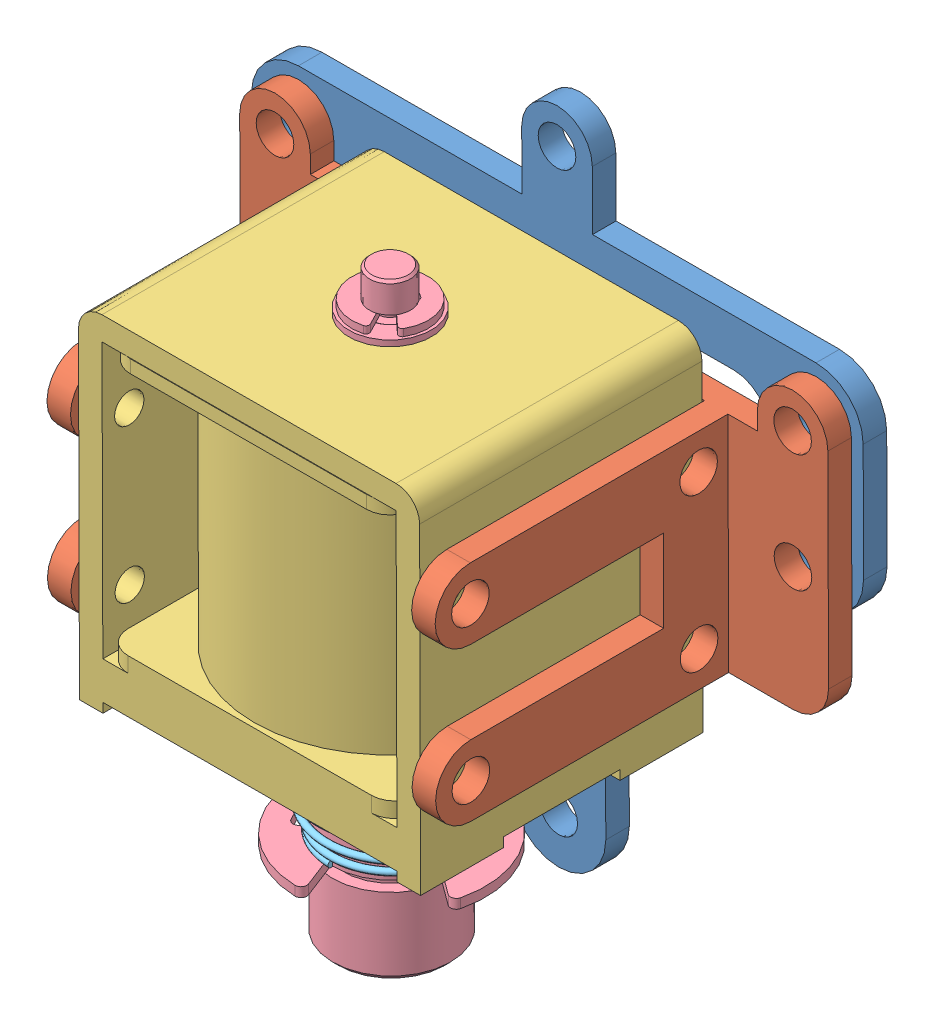
SolidWorks assembly Aimbot-S Swing, configuration Default. Lengths in mm.
Overall size (52.17 56.16 28.9).
6 component instances, 5 part files, 8 mates.
Components (placement in the parent):
- Aimbot Swing-1: Aimbot Swing [Default] at (64.9586 191.5313 171.8045) x (0.999995 0.003011 0) z (0.003011 -0.999995 0) size (52 2 56)
- CB1029 Kicker Stand-2: CB1029 Kicker Stand [Default] at (79.5263 169.075 197.7045) x (0 0 -1) z (0.999995 0.003011 0) size (26.9 23.5 50)
- INPUT kicker-4: INPUT kicker [Default] at (67.8693 174.4365 188.2528) x (-0.999995 -0.003011 0) z (0 0 1) size (29 49.3 24.1)
  - Part5^w_cb1029A-1: Part5^w_cb1029A [Default] at (2.8592 11.2966 11.7516) size (29 29.6 24.1)
  - Part1^w_cb1029A_pl-1: Part1^w_cb1029A_pl [Default] at (2.8592 29.7903 -0.2484) x (-0.794223 0 -0.607626) z (0 1 0) size (16 14.34 49.3)
  - w_21053081-1: w_21053081 [Default] at (2.8631 13.1716 -0.3303) size (16.55 9.4 16.57)
Mates (geometry in assembly coordinates):
- Coincident17: coincident anti-aligned: plane of Aimbot Swing-1 through (64.9586 191.5313 173.8045) normal (0 0 1); plane of CB1029 Kicker Stand-2 through (79.5353 166.075 173.8045) normal (0 0 -1)
- Coincident21: coincident anti-aligned: plane of CB1029 Kicker Stand-2 through (50.5264 168.9877 197.7045) normal (0.999995 0.003011 0); plane of INPUT kicker-4/Part5^w_cb1029A-1 through (50.4692 187.9876 176.0045) normal (-0.999995 -0.003011 0)
- Concentric45: concentric aligned: cylinder of CB1029 Kicker Stand-2 through (81.4872 182.081 178.3045) axis (-0.999995 -0.003011 0) radius 1.6; cylinder of INPUT kicker-4/Part5^w_cb1029A-1 through (79.4872 182.075 178.3045) axis (-0.999995 -0.003011 0) radius 1.25
- Concentric46: concentric aligned: cylinder of CB1029 Kicker Stand-2 through (81.5263 169.081 197.7045) axis (-0.999995 -0.003011 0) radius 1.6; cylinder of INPUT kicker-4/Part5^w_cb1029A-1 through (79.5263 169.075 197.7045) axis (-0.999995 -0.003011 0) radius 1.25
- Concentric49: concentric aligned: cylinder of Aimbot Swing-1 through (86.9736 186.5975 173.8045) axis (0 0 -1) radius 1.6; cylinder of CB1029 Kicker Stand-2 through (86.9736 186.5975 183.8045) axis (0 0 -1) radius 1.6
- Concentric50: concentric aligned: cylinder of Aimbot Swing-1 through (42.9738 186.465 173.8045) axis (0 0 -1) radius 1.6; cylinder of CB1029 Kicker Stand-2 through (42.9738 186.465 183.8045) axis (0 0 -1) radius 1.6
- Concentric51: concentric aligned: cylinder of Aimbot Swing-1 through (43.0039 176.4651 173.8045) axis (0 0 -1) radius 1.6; cylinder of CB1029 Kicker Stand-2 through (43.0039 176.4651 183.8045) axis (0 0 -1) radius 1.6
- Concentric52: concentric aligned: cylinder of Aimbot Swing-1 through (87.0037 176.5976 173.8045) axis (0 0 -1) radius 1.6; cylinder of CB1029 Kicker Stand-2 through (87.0037 176.5976 183.8045) axis (0 0 -1) radius 1.6
